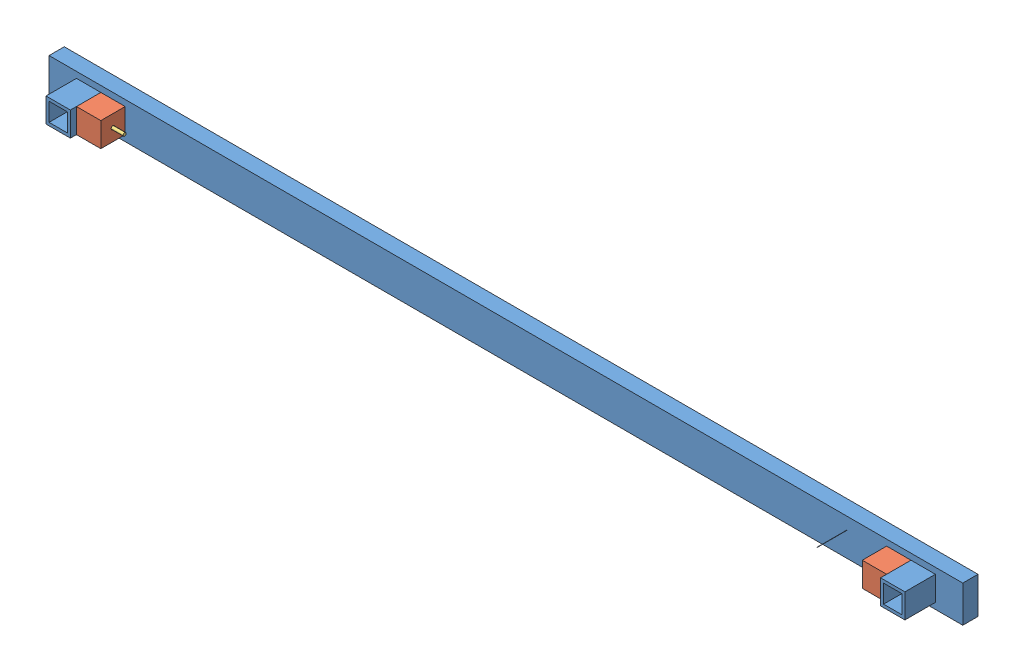
SolidWorks assembly rack MB, configuration Default. Lengths in mm.
Overall size (750 30.5 37.5).
5 component instances, 3 part files, 10 mates.
Components (placement in the parent):
- rack of MB-1: rack of MB [Default] at (194.1898 279.7056 439.4165) size (750 30.5 37.5)
- lach body-1: lach body [Default] at (516.6898 304.7056 461.9165) x (1 0 0) z (0 0 -1) size (20 20 20)
- lach body-2: lach body [Default] at (-128.3102 304.7056 461.9165) x (1 0 0) z (0 0 -1) size (20 20 20)
- lach lock-1: lach lock [Default] at (-148.7175 294.7056 461.9165) x (1 0 0) z (0 0 -1) size (40 4.91 4.91)
- lach lock-2: lach lock [Default] at (539.0695 294.7056 461.9165) x (-1 0 0) z (0 0 -1) size (40 4.91 4.91)
Mates (geometry in assembly coordinates):
- Concentric3: concentric aligned: circle of rack of MB-1; circle of lach body-2
- Coincident6: coincident anti-aligned: plane of rack of MB-1 through (569.1898 309.7056 451.9165) normal (0 0 1); plane of lach body-2 through (-118.3102 284.7056 451.9165) normal (0 0 -1)
- Coincident7: coincident anti-aligned: plane of rack of MB-1 through (-138.3102 304.7056 476.9165) normal (1 0 0); plane of lach body-2 through (-138.3102 284.7056 451.9165) normal (-1 0 0)
- Concentric4: concentric anti-aligned: circle of rack of MB-1; circle of lach body-1
- Coincident9: coincident anti-aligned: plane of rack of MB-1 through (569.1898 309.7056 451.9165) normal (0 0 1); plane of lach body-1 through (526.6898 284.7056 451.9165) normal (0 0 -1)
- Coincident10: coincident anti-aligned: plane of rack of MB-1 through (526.6898 304.7056 476.9165) normal (-1 0 0); plane of lach body-1 through (526.6898 284.7056 451.9165) normal (1 0 0)
- Concentric5: concentric aligned: circle of lach body-1; circle of lach lock-2
- Angle1: planar angle = 1.570796 rad anti-aligned: plane of lach lock-2 through (537.8197 297.2056 460.6444) normal (0.700854 0 0.713305); plane of rack of MB-1 through (544.1898 287.2056 451.9165) normal (0 1 0)
- Concentric6: concentric anti-aligned: circle of lach body-2; circle of lach lock-1
- Angle2: planar angle = 1.570796 rad aligned: plane of lach lock-1 through (-147.4677 292.2056 460.6444) normal (-0.700854 0 0.713305); plane of rack of MB-1 through (-140.8102 287.2056 451.9165) normal (0 1 0)
